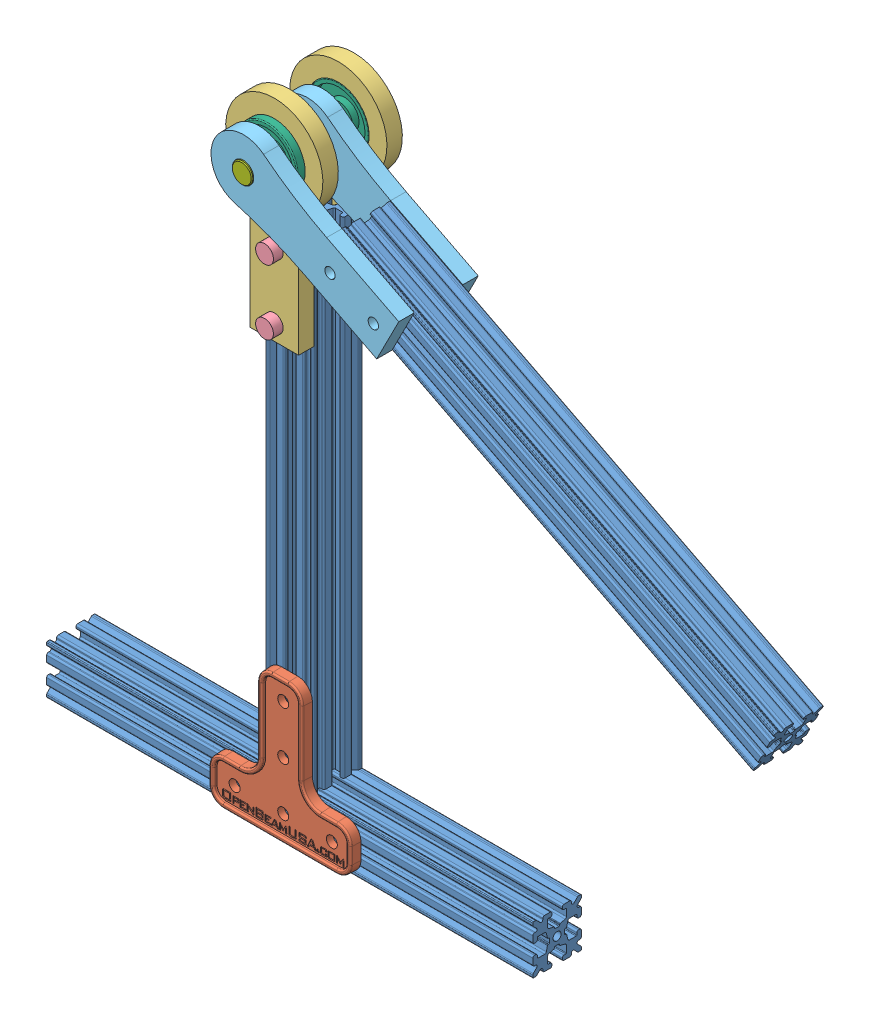
SolidWorks assembly pendulum, configuration Default. Lengths in mm.
Overall size (234.28 200.13 38.1).
13 component instances, 7 part files, 24 mates.
Components (placement in the parent):
- OpenBeam 1515 Aluminum Extrusion-1: OpenBeam 1515 Aluminum Extrusion [150 mm] at (75 -7.5 7.5) x (0 0 1) z (1 0 0) size (15 15 150)
- OpenBeam 1515 Aluminum Extrusion-2: OpenBeam 1515 Aluminum Extrusion [150 mm] at (0 0 7.5) x (0 0 1) z (0 -1 0) size (15 15 150)
- TL625-000101-002_-_T_Plate_OpenBeam_1515-1: TL625-000101-002_-_T_Plate_OpenBeam_1515 [Default] at (0 0 15) size (44 44 3)
- bearing clevis half-1: bearing clevis half [Default] at (0 120.13 15) x (1 0 0) z (0 -1 0) size (30 4.76 65)
- bearing clevis half-2: bearing clevis half [Default] at (0 120 0) x (-1 0 0) z (0 -1 0) size (30 4.76 65)
- simplified_M3_socket_head_cap_screw-1: simplified_M3_socket_head_cap_screw [M3 x  8] at (0 145 19.7752) x (1 0 0) z (0 -1 0) size (5.5 11 5.5)
- simplified_M3_socket_head_cap_screw-2: simplified_M3_socket_head_cap_screw [M3 x 8] at (0 125 19.7752) x (1 0 0) z (0 -1 0) size (5.5 11 5.5)
- shaft clevis half-1: shaft clevis half [Default] at (44.5346 147.3996 9.525) x (-0.454609 -0.890691 0) z (0.890691 -0.454609 0) size (20 4.76 60)
- generic ball bearing-1: generic ball bearing [0.250 x 0.75] at (0 170.13 22.1438) x (0 0 -1) z (1 0 0) size (7.14 19.05 19.05)
- generic ball bearing-2: generic ball bearing [0.250 x 0.75] at (0 170 0) x (0 0 -1) z (1 0 0) size (7.14 19.05 19.05)
- OpenBeam 1515 Aluminum Extrusion-3: OpenBeam 1515 Aluminum Extrusion [150 mm] at (155.8709 90.5734 17.025) x (0 0 1) z (0.890691 -0.454609 0) size (15 15 150)
- shaft clevis half-2: shaft clevis half [Default] at (44.5346 147.3996 29.2875) x (-0.454609 -0.890691 0) z (0.890691 -0.454609 0) size (20 4.76 60)
- generic_dowel_pin-1: generic_dowel_pin [0.25 x 1.5] at (0 170 10.7499) x (0 0 1) z (-0.99675 -0.080556 0) size (38.1 6.35 6.35)
Mates (geometry in assembly coordinates):
- Coincident1: coincident aligned: plane of OpenBeam 1515 Aluminum Extrusion-1 through (-75 0 9.6) normal (0 1 0); plane of assembly through (0 0 0) normal (0 1 0)
- Symmetric1: symmetric aligned: plane of OpenBeam 1515 Aluminum Extrusion-1 through (-75 -4.9529 8.1255) normal (-1 0 0); plane of OpenBeam 1515 Aluminum Extrusion-1 through (75 -4.9529 8.1255) normal (1 0 0); plane of assembly through (0 0 0) normal (1 0 0)
- Coincident2: coincident anti-aligned: plane of OpenBeam 1515 Aluminum Extrusion-1 through (-75 -5.4 0) normal (0 0 -1); plane of assembly through (0 0 0) normal (0 0 1)
- Coincident3: coincident anti-aligned: plane of OpenBeam 1515 Aluminum Extrusion-1 through (-75 0 9.6) normal (0 1 0); plane of OpenBeam 1515 Aluminum Extrusion-2 through (2.5471 0 8.1255) normal (0 -1 0)
- Coincident4: coincident aligned: plane of OpenBeam 1515 Aluminum Extrusion-1 through (-75 -5.4 0) normal (0 0 -1); plane of OpenBeam 1515 Aluminum Extrusion-2 through (-3.9 150 0) normal (0 0 -1)
- Coincident5: coincident anti-aligned: plane of OpenBeam 1515 Aluminum Extrusion-2; plane of assembly through (0 0 0) normal (1 0 0)
- Coincident6: coincident anti-aligned: plane of OpenBeam 1515 Aluminum Extrusion-2 through (-2.1 150 15) normal (0 0 1); plane of TL625-000101-002_-_T_Plate_OpenBeam_1515-1 through (0 0 15) normal (0 0 -1)
- Coincident7: coincident: line of TL625-000101-002_-_T_Plate_OpenBeam_1515-1 through (0 22.5 15) axis (0 -1 0); plane of assembly
- Coincident8: coincident: line of TL625-000101-002_-_T_Plate_OpenBeam_1515-1 through (15 -7.5 15) axis (-1 0 0); plane of OpenBeam 1515 Aluminum Extrusion-1
- Coincident10: coincident: plane of OpenBeam 1515 Aluminum Extrusion-2; line of bearing clevis half-1 through (0 120.13 15) axis (0 1 0)
- Coincident16: coincident anti-aligned: plane of OpenBeam 1515 Aluminum Extrusion-2 through (3.9 150 15) normal (0 0 1); plane of bearing clevis half-1 through (22.9167 150.13 15) normal (0 0 -1)
- Concentric4: concentric anti-aligned: cylinder of bearing clevis half-1 through (0 170.13 19.7625) axis (0 0 -1) radius 9.525; cylinder of generic ball bearing-1 through (0 170.13 26.9758) axis (0 0 1) radius 9.525
- Coincident17: coincident aligned: plane of bearing clevis half-1 through (22.9167 150.13 15) normal (0 0 -1); plane of generic ball bearing-1 through (0 178.385 15) normal (0 0 -1)
- Concentric5: concentric aligned: cylinder of bearing clevis half-2 through (0 170 -4.7625) axis (0 0 1) radius 9.525; cylinder of generic ball bearing-2 through (0 170 4.8321) axis (0 0 1) radius 9.525
- Coincident18: coincident aligned: plane of bearing clevis half-2 through (-22.9167 150 0) normal (0 0 1); plane of generic ball bearing-2 through (0 179.2202 0) normal (0 0 1)
- Concentric6: concentric anti-aligned: cylinder of bearing clevis half-1 through (0 170.13 19.7625) axis (0 0 -1) radius 9.525; cylinder of shaft clevis half-1 through (0 170.13 4.7625) axis (0 0 1) radius 3.175
- Distance1: distance = 15 mm anti-aligned: plane of shaft clevis half-1 through (-33.9906 48.5418 4.7625) normal (0 0 -1); plane of bearing clevis half-1 through (22.9167 150.13 19.7625) normal (0 0 1)
- Coincident22: coincident anti-aligned: plane of shaft clevis half-1 through (-33.9906 48.5418 9.525) normal (0 0 1); plane of OpenBeam 1515 Aluminum Extrusion-3 through (20.4943 155.2911 9.525) normal (0 0 -1)
- Coincident23: coincident aligned: plane of shaft clevis half-1 through (25.6768 165.445 4.7625) normal (0.454609 0.890691 0); plane of OpenBeam 1515 Aluminum Extrusion-3 through (25.6768 165.445 13.125) normal (0.454609 0.890691 0)
- Coincident24: coincident: line of shaft clevis half-1 through (25.6768 165.445 4.7625) axis (0 0 1); plane of OpenBeam 1515 Aluminum Extrusion-3 through (23.4252 161.0334 17.6505) normal (-0.890691 0.454609 0)
- Coincident25: coincident anti-aligned: plane of OpenBeam 1515 Aluminum Extrusion-3 through (24.0403 162.2385 24.525) normal (0 0 1); plane of shaft clevis half-2 through (-33.9906 48.5418 24.525) normal (0 0 -1)
- Concentric7: concentric aligned: cylinder of shaft clevis half-1 through (0 170.13 4.7625) axis (0 0 1) radius 3.175; cylinder of shaft clevis half-2 through (0 170.13 24.525) axis (0 0 1) radius 3.175
- Coincident26: coincident aligned: plane of shaft clevis half-1 through (25.6768 165.445 4.7625) normal (0.454609 0.890691 0); plane of shaft clevis half-2 through (25.6768 165.445 24.525) normal (0.454609 0.890691 0)
- Concentric8: concentric anti-aligned: cylinder of generic ball bearing-2 through (0 170 4.8321) axis (0 0 1) radius 3.175; cylinder of generic_dowel_pin-1 through (0 170 29.7999) axis (0 0 -1) radius 3.175
